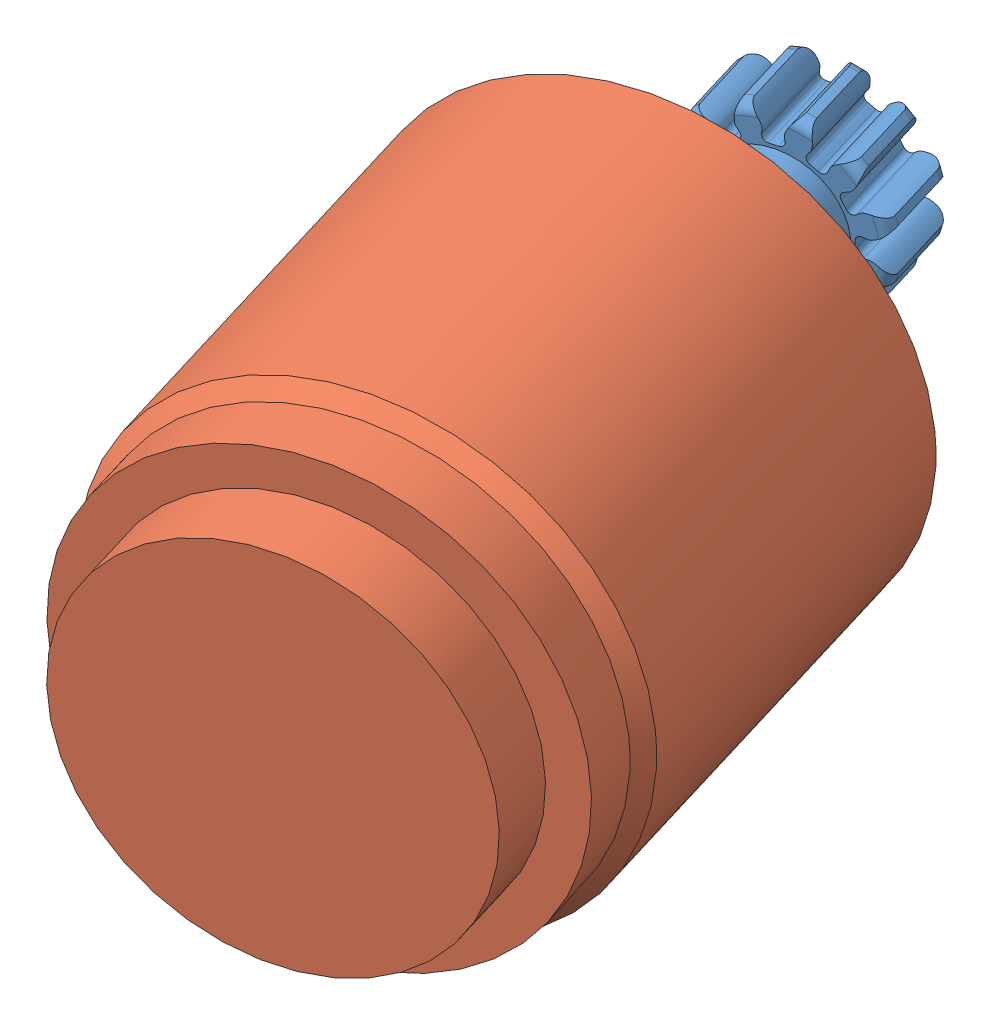
SolidWorks assembly Assem1, configuration Default. Lengths in mm.
Overall size (24.06 18.05 32.57).
2 component instances, 2 part files, 1 mates.
Components (placement in the parent):
- 12g-1: 12g [Default] at (-53.8931 -7.3217 28.633) x (0.266681 -0.03453 0.963166) z (-0.935433 -0.249888 0.250044) size (7.03 7.06 7.06)
- 1717SR-1: 1717SR [Default] at (-51.727 -7.6021 36.4562) x (0.963773 0.004691 -0.266681) z (0.266681 -0.03453 0.963166) size (17 17 28.5)
Mates (geometry in assembly coordinates):
- Concentric4: concentric aligned: cylinder of 12g-1 through (-53.413 -7.3838 30.3667) axis (0.266681 -0.03453 0.963166) radius 1; cylinder of 1717SR-1 through (-54.1538 -7.2879 27.6914) axis (0.266681 -0.03453 0.963166) radius 0.75
